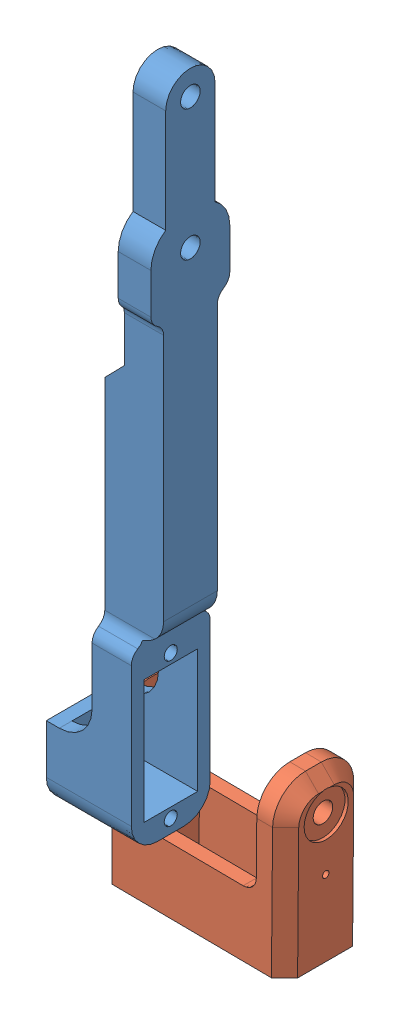
SolidWorks assembly Assem2, configuration 默认. Lengths in mm.
Overall size (28.63 119.33 23.47).
2 component instances, 2 part files, 0 mates.
Components (placement in the parent):
- 机械臂2自由1-1: 机械臂2自由1 [默认] at (-18.9048 -57.7963 105.889) size (16 102.91 12.07)
- 俯仰1-1: 俯仰1 [默认] at (-24.202 -57.3219 92.9084) x (-0.008727 -0.999962 0) z (0 0 1) size (25 28.42 12.41)
